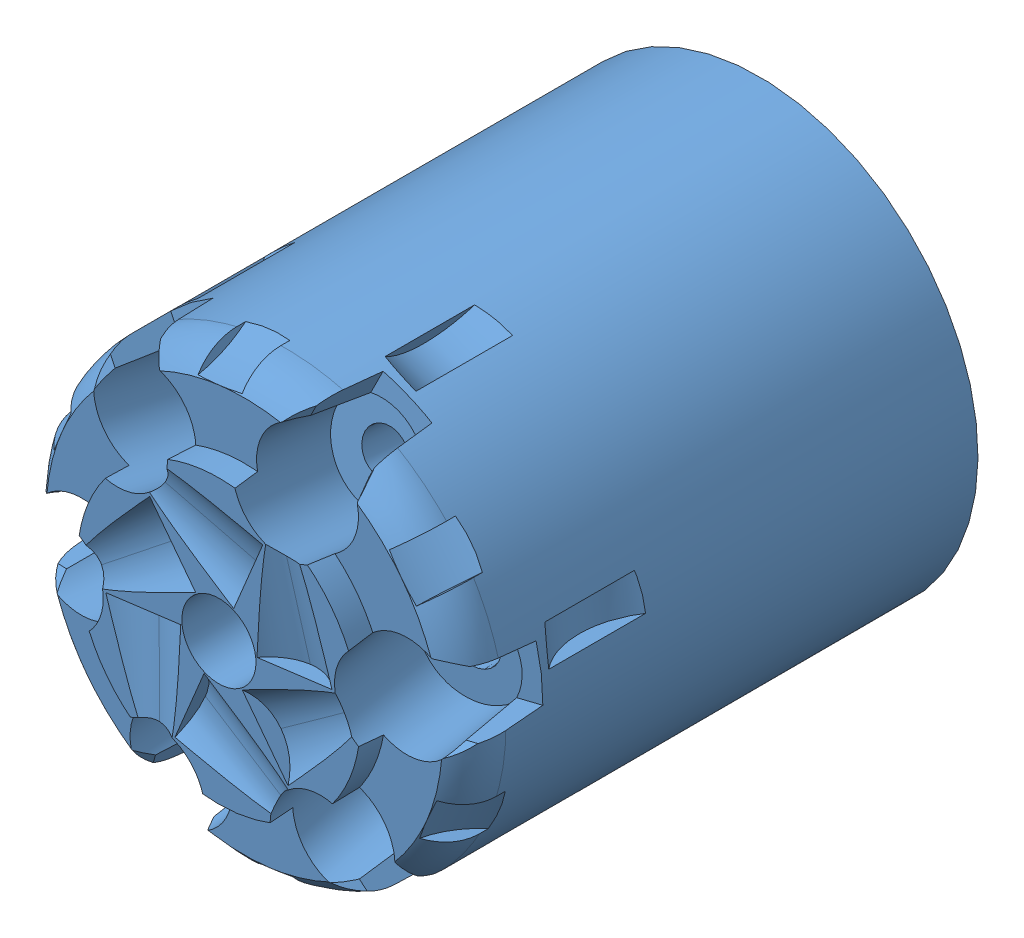
SolidWorks assembly Assem2, configuration Default. Lengths in mm.
Overall size (43.32 43.9 52.12).
13 component instances, 3 part files, 2 mates.
Components (placement in the parent):
- Cylinder.38-1: Cylinder.38 [Default] at (8.3039 42.316 31.2102) size (43.32 43.9 52.12)
- Inner_cylinder.38-1: Inner_cylinder.38 [Default] at (15.0558 44.1547 24.2518) x (0.372005 -0.928231 0) z (0 0 1) size (9.65 9.65 21.34)
- Piston.38-1: Piston.38 [Default] at (15.0558 44.1547 45.6219) x (0.99879 -0.049172 0) z (0 0 -1) size (9.65 9.65 17)
- Piston.38-2: Piston.38 [Default] at (2.4597 42.533 45.6219) x (0.541979 0.840392 0) z (0 0 -1) size (9.65 9.65 17)
- Piston.38-3: Piston.38 [Default] at (-2.4338 30.8136 45.6219) x (-0.456811 0.889564 0) z (0 0 -1) size (9.65 9.65 17)
- Piston.38-4: Piston.38 [Default] at (5.2687 20.716 45.6219) x (-0.99879 0.049172 0) z (0 0 -1) size (9.65 9.65 17)
- Piston.38-5: Piston.38 [Default] at (17.8647 22.3377 45.6219) x (-0.541979 -0.840392 0) z (0 0 -1) size (9.65 9.65 17)
- Piston.38-6: Piston.38 [Default] at (22.7583 34.0571 45.6219) x (0.456811 -0.889564 0) z (0 0 -1) size (9.65 9.65 17)
- Inner_cylinder.38-2: Inner_cylinder.38 [Default] at (2.4597 42.533 24.2518) x (0.989874 -0.141949 0) z (0 0 1) size (9.65 9.65 21.34)
- Inner_cylinder.38-3: Inner_cylinder.38 [Default] at (-2.4338 30.8136 24.2518) x (0.617868 0.786281 0) z (0 0 1) size (9.65 9.65 21.34)
- Inner_cylinder.38-4: Inner_cylinder.38 [Default] at (5.2687 20.716 24.2518) x (-0.372005 0.928231 0) z (0 0 1) size (9.65 9.65 21.34)
- Inner_cylinder.38-5: Inner_cylinder.38 [Default] at (17.8647 22.3377 24.2518) x (-0.989874 0.141949 0) z (0 0 1) size (9.65 9.65 21.34)
- Inner_cylinder.38-6: Inner_cylinder.38 [Default] at (22.7583 34.0571 24.2518) x (-0.617868 -0.786281 0) z (0 0 1) size (9.65 9.65 21.34)
Mates (geometry in assembly coordinates):
- Concentric1: concentric: cylinder of Cylinder.38-1 through (15.0558 44.1547 -1.106) axis (0 0 1) radius 4.826; cylinder of Inner_cylinder.38-1 through (15.0558 44.1547 55.2398) axis (0 0 -1) radius 4.826
- Concentric2: concentric: circle of Cylinder.38-1; circle of Piston.38-1
